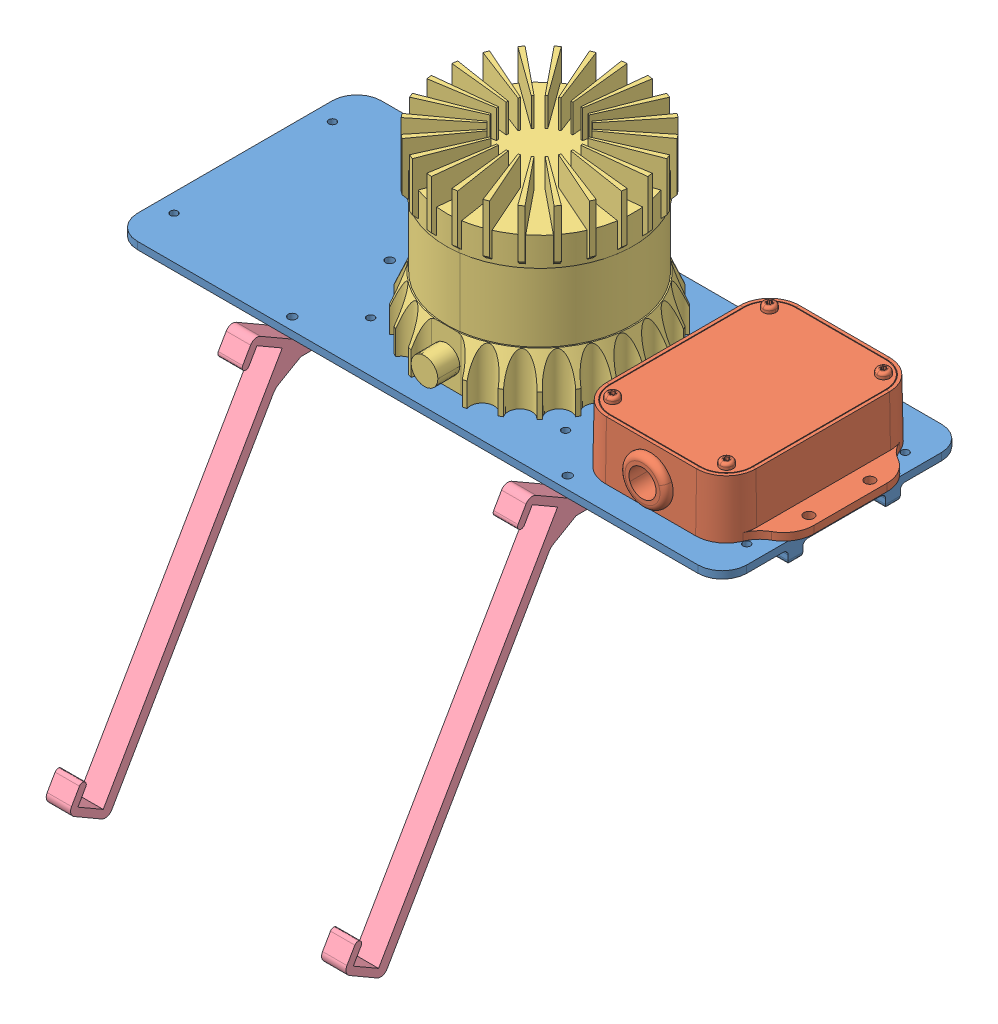
SolidWorks assembly LiDAR_asm, configuration 默认. Lengths in mm.
Overall size (252.75 208.34 190.95).
5 component instances, 4 part files, 10 mates.
Components (placement in the parent):
- LiDAR_board-1: LiDAR_board [默认] at (-55.9292 6.4836 0) size (250 9 100)
- Interface-box-1: Interface-box [默认] at (29.7439 12.4836 0.1387) size (84.15 26.02 83.31)
- ouster.step-1: ouster.step [默认] at (-55.9292 9.4836 0) x (-0.991445 0 0.130526) z (-0.130526 0 -0.991445) size (86.46 73.5 90.77)
- screenhold-1: screenhold [默认] at (-107.4292 -1.5164 25) x (-1 0 0) z (0 0 -1) size (10 139.74 140.95)
- screenhold-2: screenhold [默认] at (5.5708 -1.5164 25) x (-1 0 0) z (0 0 -1) size (10 139.74 140.95)
Mates (geometry in assembly coordinates):
- 重合2: coincident anti-aligned: plane of LiDAR_board-1 through (-55.9292 9.4836 0) normal (0 1 0); plane of Interface-box-1 through (1.6728 9.4836 0.1387) normal (0 -1 0)
- 重合5: coincident anti-aligned: plane of LiDAR_board-1 through (-55.9292 9.4836 0) normal (0 1 0); plane of ouster.step-1 through (-55.9292 9.4836 0) normal (0 -1 0)
- 同心1: concentric anti-aligned: cylinder of LiDAR_board-1 through (-73.9292 0.4826 31.1769) axis (0 1 0) radius 1.7; cylinder of ouster.step-1 through (-73.9292 14.4836 31.1769) axis (0 -1 0) radius 1.5
- 同心2: concentric anti-aligned: cylinder of LiDAR_board-1 through (-24.7523 0.4826 -18) axis (0 1 0) radius 1.7; cylinder of ouster.step-1 through (-24.7523 14.4836 -18) axis (0 -1 0) radius 1.5
- 同心3: concentric anti-aligned: cylinder of LiDAR_board-1 through (-112.4292 0.4826 5) axis (0 1 0) radius 1.7; cylinder of screenhold-1 through (-112.4292 6.4846 5) axis (0 -1 0) radius 1.45
- 同心4: concentric anti-aligned: cylinder of LiDAR_board-1 through (-112.4292 0.4826 45) axis (0 1 0) radius 1.7; cylinder of screenhold-1 through (-112.4292 6.4846 45) axis (0 -1 0) radius 1.45
- 重合6: coincident anti-aligned: plane of LiDAR_board-1 through (-55.9292 6.4836 0) normal (0 -1 0); plane of screenhold-1 through (-94.4862 6.4836 0) normal (0 1 0)
- 同心5: concentric anti-aligned: cylinder of LiDAR_board-1 through (0.5708 0.4826 45) axis (0 1 0) radius 1.7; cylinder of screenhold-2 through (0.5708 6.4846 45) axis (0 -1 0) radius 1.45
- 同心6: concentric anti-aligned: cylinder of LiDAR_board-1 through (0.5708 0.4826 5) axis (0 1 0) radius 1.7; cylinder of screenhold-2 through (0.5708 6.4846 5) axis (0 -1 0) radius 1.45
- 重合8: coincident anti-aligned: plane of LiDAR_board-1 through (-55.9292 6.4836 0) normal (0 -1 0); plane of screenhold-2 through (18.5138 6.4836 0) normal (0 1 0)
